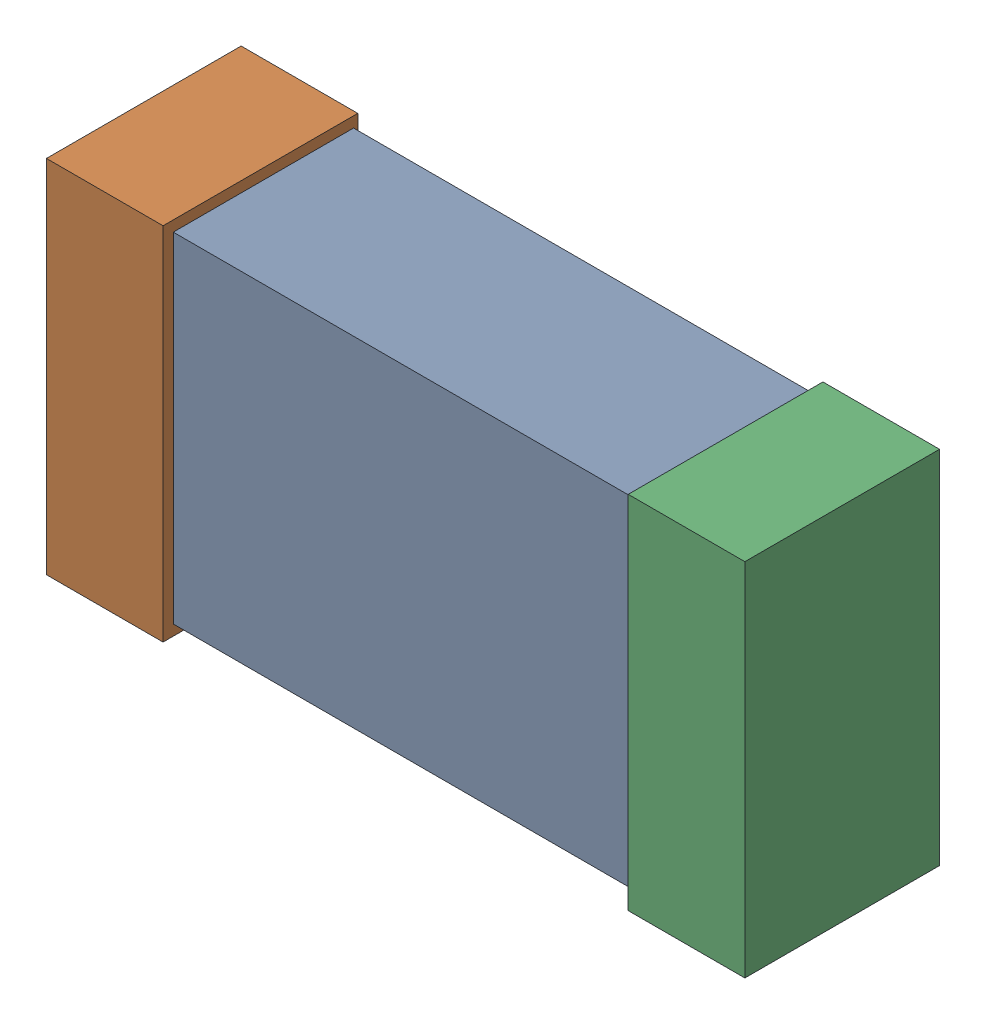
SolidWorks assembly R32, configuration Default. Lengths in mm.
Overall size (1.65 0.85 0.46).
6 component instances, 2 part files, 0 mates.
Components (placement in the parent):
- 432120720_26-1: 432120720_26 [Default] at (15.0566 23.9499 -0.8615) size (1.5 0.8 0.42)
  - Extruded (12)-1: Extruded (12) [Default] at origin size (1.5 0.8 0.42)
- 432120464_54-1: 432120464_54 [Default] at (14.3708 23.9499 -0.8715) size (0.28 0.85 0.46)
  - Extruded (11)-1: Extruded (11) [Default] at origin size (0.28 0.85 0.46)
- 432120464_55-1: 432120464_55 [Default] at (15.7423 23.9499 -0.8715) size (0.28 0.85 0.46)
  - Extruded (11)-1: Extruded (11) [Default] at origin size (0.28 0.85 0.46)
